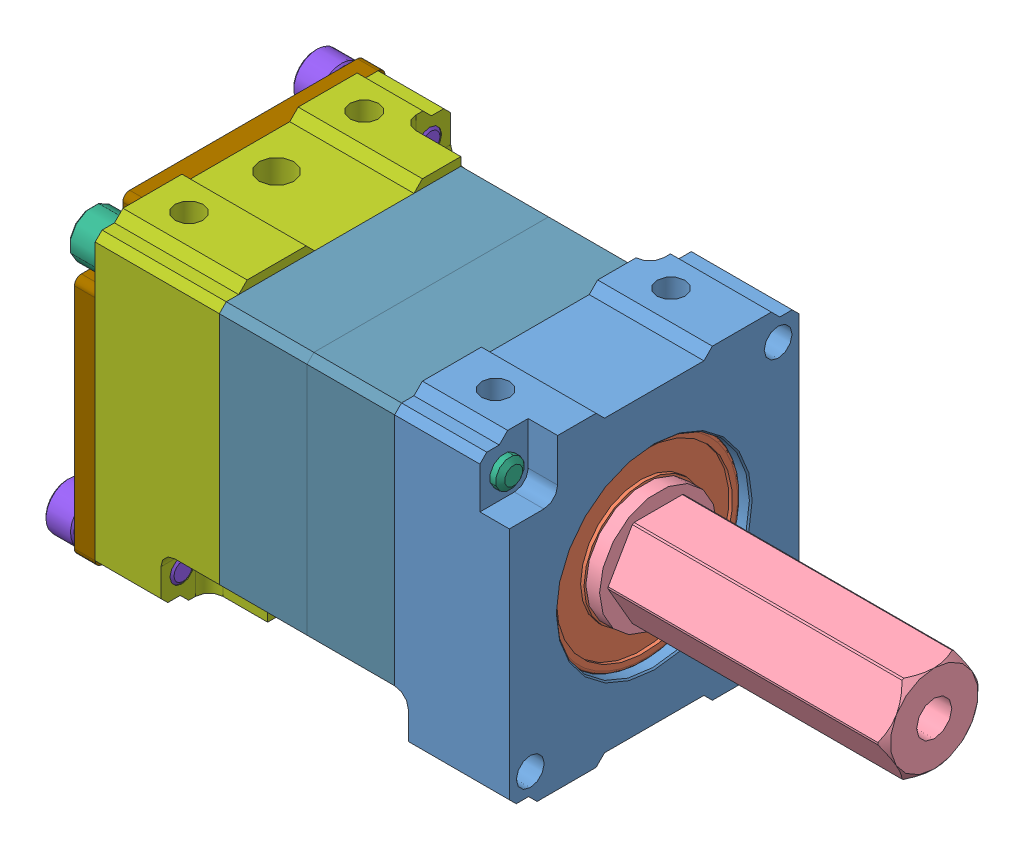
SolidWorks assembly VersaPlanetary_v2_Two_Stage_100_1_with_BAG, configuration Default. Lengths in mm.
Overall size (107.66 49.05 49.3).
37 component instances, 17 part files, 0 mates.
Components (placement in the parent):
- 217-2625-026 Rev1-1: 217-2625-026 Rev1 [Default] at (-6.5 22.225 0) x (0 -1 0) z (-1 0 0) size (44.45 42 18.13)
- 217-2742-001 Rev4-1: 217-2742-001 Rev4 [Default] at (0.2002 22.225 0) x (1 0 0) z (0 -0.092627 0.995701) size (7 28 28)
- 217-2742-001 Rev4-2: 217-2742-001 Rev4 [Default] at (8.2002 22.225 0) size (7 28 28)
- 217-2625-017 Rev1_9714K61-1: 217-2625-017 Rev1_9714K61 [Default] at (7.42 22.3002 -0.342) x (0 0.56703 0.823697) z (0 -0.823697 0.56703) size (28.51 4.98 30.18)
- 217-2625-003 Rev1-1: 217-2625-003 Rev1 [Default] at (7.4478 22.225 0) x (0 -1 0) z (1 0 0) size (17 17 64.12)
- 217-2625-018 Rev1_98541A410-1: 217-2625-018 Rev1_98541A410 [Default] at (-0.7046 22.225 0) x (1 0 0) z (0 -0.017452 0.999848) size (1 19.6 17.4)
- 832-2250-Base-Kit-Screw_SSA0832-0500ZC-1: 832-2250-Base-Kit-Screw_SSA0832-0500ZC [Default] at (-43.4 4.725 -17.5) x (0 -0.767799 -0.640691) z (0 0.640691 -0.767799) size (6.73 61.21 6.73)
- 832-2250-Base-Kit-Screw_SSA0832-0500ZC-2: 832-2250-Base-Kit-Screw_SSA0832-0500ZC [Default] at (-43.4 39.725 17.5) x (0 0.961307 0.275478) z (0 -0.275478 0.961307) size (6.73 61.21 6.73)
- 217-2625-025 Rev1-1: 217-2625-025 Rev1 [Default] at (-35.9 22.225 0) x (0 -1 0) z (-1 0 0) size (44.45 42 18)
- 217-4649-002 Rev1_SSA0832-0500ZC-1: 217-4649-002 Rev1_SSA0832-0500ZC [Default] at (-46.4 4.2645 17.9605) x (0 0.33842 -0.940995) z (0 0.940995 0.33842) size (6.73 16.76 6.73)
- 217-4649-002 Rev1_SSA0832-0500ZC-2: 217-4649-002 Rev1_SSA0832-0500ZC [Default] at (-46.4 40.1855 -17.9605) x (0 -0.308932 -0.951084) z (0 0.951084 -0.308932) size (6.73 16.76 6.73)
- 217-2822-003 Rev4-1: 217-2822-003 Rev4 [Default] at (-44.9 22.225 0) x (0 -1 0) z (-1 0 0) size (42 42 4.8)
- 217-2820 Rev1_Public-1: 217-2820 Rev1_Public [Default] at (-4.6546 22.225 0) x (0 -0.456494 0.889726) z (-1 0 0) size (39.26 38.9 17.4)
  - 217-2625-100-1: 217-2625-100 [Default] at origin size (39.26 38.9 12.7)
    - 217-2625-008 Rev1-1: 217-2625-008 Rev1 [Default] at origin size (34.7 34.7 4.7)
    - 217-2625-010 Rev1-1: 217-2625-010 Rev1 [Default] at (0 10.193 3.65) x (0.999813 0.019336 0) z (0 0 1) size (4 4 12)
    - 217-2625-010 Rev1-2: 217-2625-010 Rev1 [Default] at (8.691 -5.3258 3.65) size (4 4 12)
    - 217-2625-010 Rev1-3: 217-2625-010 Rev1 [Default] at (-8.691 -5.3258 3.65) size (4 4 12)
    - 217-2625-005 Rev1_Planet_Revolving_Follower01-1: 217-2625-005 Rev1_Planet_Revolving_Follower01 [Default] at (8.691 -5.3258 6.35) x (0.932816 0.360354 0) z (0 0 1) size (16.91 16.92 8)
    - 217-2625-005 Rev1_Planet_Revolving_Follower01-2: 217-2625-005 Rev1_Planet_Revolving_Follower01 [Default] at (-8.691 -5.3258 6.35) x (-0.932788 -0.360426 0) z (0 0 1) size (16.91 16.92 8)
    - 217-2625-005 Rev1_Planet_Revolving_Follower01-3: 217-2625-005 Rev1_Planet_Revolving_Follower01 [Default] at (0 10.193 6.35) x (0.893583 0.448898 0) z (0 0 1) size (16.91 16.92 8)
  - 217-2625-007 Rev1_Public-1: 217-2625-007 Rev1_Public [Default] at (0 0 6.7) x (0.992772 0.120019 0) z (0 0 1) size (14.49 14.49 12.72)
- 217-2816-001 Rev1-1: 217-2816-001 Rev1 [Default] at (-6.35 22.225 0) x (0 -1 0) z (1 0 0) size (42 42 14.5)
- 217-2820 Rev1_Public-2: 217-2820 Rev1_Public [Default] at (-17.15 22.225 0) x (0 0.184082 0.982911) z (-1 0 0) size (39.26 38.9 17.4)
  - 217-2625-100-1: 217-2625-100 [Default] at origin size (39.26 38.9 12.7)
    - 217-2625-008 Rev1-1: 217-2625-008 Rev1 [Default] at origin size (34.7 34.7 4.7)
    - 217-2625-010 Rev1-1: 217-2625-010 Rev1 [Default] at (0 10.193 3.65) x (0.999813 0.019336 0) z (0 0 1) size (4 4 12)
    - 217-2625-010 Rev1-2: 217-2625-010 Rev1 [Default] at (8.691 -5.3258 3.65) size (4 4 12)
    - 217-2625-010 Rev1-3: 217-2625-010 Rev1 [Default] at (-8.691 -5.3258 3.65) size (4 4 12)
    - 217-2625-005 Rev1_Planet_Revolving_Follower01-1: 217-2625-005 Rev1_Planet_Revolving_Follower01 [Default] at (8.691 -5.3258 6.35) x (0.932816 0.360354 0) z (0 0 1) size (16.91 16.92 8)
    - 217-2625-005 Rev1_Planet_Revolving_Follower01-2: 217-2625-005 Rev1_Planet_Revolving_Follower01 [Default] at (-8.691 -5.3258 6.35) x (-0.932788 -0.360426 0) z (0 0 1) size (16.91 16.92 8)
    - 217-2625-005 Rev1_Planet_Revolving_Follower01-3: 217-2625-005 Rev1_Planet_Revolving_Follower01 [Default] at (0 10.193 6.35) x (0.893583 0.448898 0) z (0 0 1) size (16.91 16.92 8)
  - 217-2625-007 Rev1_Public-1: 217-2625-007 Rev1_Public [Default] at (0 0 6.7) x (0.992772 0.120019 0) z (0 0 1) size (14.49 14.49 12.72)
- 217-2816-001 Rev1-2: 217-2816-001 Rev1 [Default] at (-19.05 22.225 0) x (0 -1 0) z (1 0 0) size (42 42 14.5)
- 217-4649-001 Rev1-1: 217-4649-001 Rev1 [Default] at (-32.746 22.225 0) x (0 -1 0) z (1 0 0) size (18 18 13)
- 217-4649-007 Rev1_94105A824-1: 217-4649-007 Rev1_94105A824 [Default] at (-38.221 22.225 -6.7835) x (-0.996104 -0.088191 0) z (0 0 -1) size (4.83 4.83 4.9)
- 217-2625-011 Rev1-1: 217-2625-011 Rev1 [Default] at (-37.4818 22.225 0) x (0 0 1) z (0 -1 0) size (8.01 7.5 7.94)
